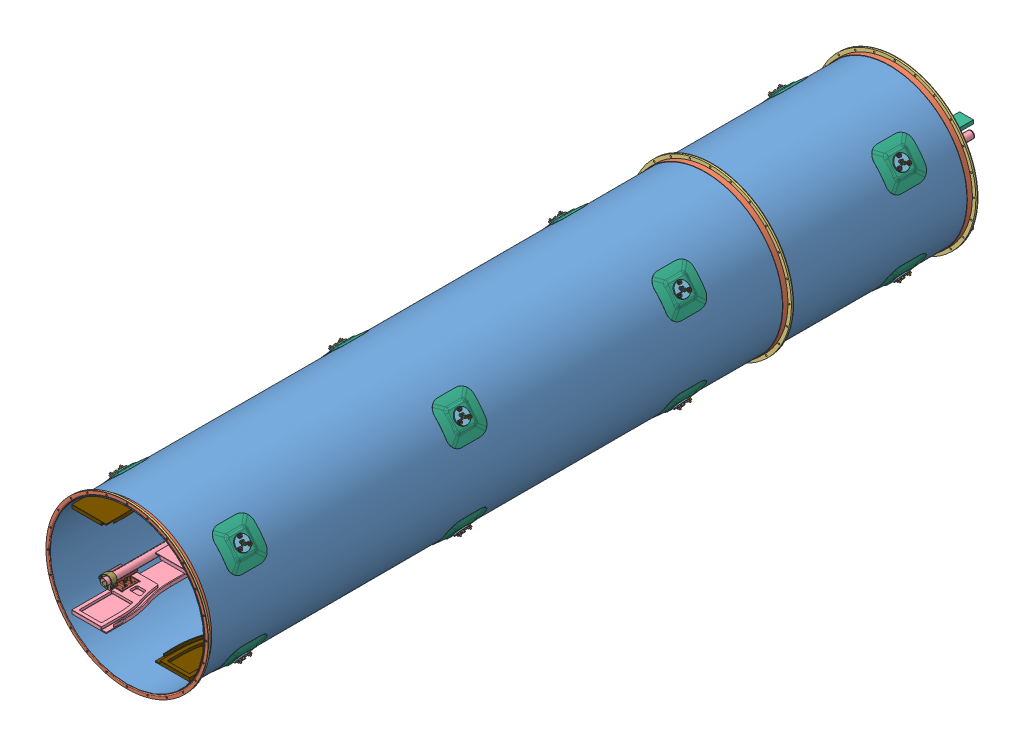
SolidWorks assembly Pixel_Insertion_Tube_asm_no_fix, configuration Default. Lengths in mm.
Overall size (454.65 454.65 2208.1).
343 component instances, 26 part files, 15 mates.
Components (placement in the parent):
- Pixel_Insertion_Tube-1: Pixel_Insertion_Tube [Default] at (0 0 -5) size (432 432 2158)
- IDS Small Flange Assy-1: IDS Small Flange Assy [Default] at (0 0 -567) x (-1 0 0) z (0 0 -1) size (454.65 454.65 20)
  - IDS Small Flange Shell-1: IDS Small Flange Shell [Default] at origin size (454.65 454.65 20)
  - IDS Small Ring-1: IDS Small Ring [Thinner] at (0 0 -6) size (454.65 454.65 4.7)
- IDS Small Flange Assy-2: IDS Small Flange Assy [Default] at (0 0 1074) x (-1 0 0) z (0 0 1) size (454.65 454.65 20)
  - IDS Small Flange Shell-1: IDS Small Flange Shell [Default] at origin size (454.65 454.65 20)
  - IDS Small Ring-1: IDS Small Ring [Thinner] at (0 0 -6) size (454.65 454.65 4.7)
- IDS Small Flange Assy-3: IDS Small Flange Assy [Default] at (0 0 -1084) x (-1 0 0) z (0 0 -1) size (454.65 454.65 20)
  - IDS Small Flange Shell-1: IDS Small Flange Shell [Default] at origin size (454.65 454.65 20)
  - IDS Small Ring-1: IDS Small Ring [Thinner] at (0 0 -6) size (454.65 454.65 4.7)
- PIT_rail_20mm_assembly_no_fix-1: PIT_rail_20mm_assembly_no_fix [on pit] at (0 0 -1134.1) size (415.12 363.39 2198)
  - PIT_rail_rc-1: PIT_rail_rc [TN] at (-158 94 2) size (138.56 101.58 2198)
    - rc-1: rc [Default] at origin size (20 20 2114)
    - rc_mount-1: rc_mount [PIT] at (0 0 208.1) size (80.85 96.81 113.59)
      - PIT_rail_foot_v2-1: PIT_rail_foot_v2 [PIT] at (-6.1826 36.9354 0) x (0.623502 0.781822 0) z (0 0 1) size (113.62 41.63 113.59)
        - PIT_rail_arm_achor_post_v2-1: PIT_rail_arm_achor_post_v2 [Default] at origin size (40 13.24 40)
        - PIT_foot_composit_v6-1: PIT_foot_composit_v6 [Default] at (0 3.7433 0) x (0 -1 0) z (0 0 1) size (12.8 113.62 113.59)
        - PIT_rail_hanger_ext_v3-1: PIT_rail_hanger_ext_v3 [Default] at (0 5.7433 -28.8) x (0 -1 0) z (0 0 1) (suppressed, hidden)
        - HX-SHCS 0.164-32x1x1-N-1: HX-SHCS 0.164-32x1x1-N [HX-SHCS 0.164-32x1x1-N] at (-3.5355 17.4089 3.5355) x (0 -1 0) z (0.991685 0 -0.128686) size (29.57 6.86 6.86)
        - HX-SHCS 0.164-32x1x1-N-2: HX-SHCS 0.164-32x1x1-N [HX-SHCS 0.164-32x1x1-N] at (3.5355 17.4089 -3.5355) x (0 -1 0) z (0 0 1) size (29.57 6.86 6.86)
        - HI-TIGUE-HLT452-5-3-1: HI-TIGUE-HLT452-5-3 [Default] at (15.5 6.9433 0) x (-0.837169 0 -0.546944) z (-0.546944 0 0.837169) size (7.98 14.34 7.98)
        - HI-TIGUE-HLT452-5-3-2: HI-TIGUE-HLT452-5-3 [Default] at (-7.75 6.9433 13.4234) x (-0.837169 0 -0.546944) z (-0.546944 0 0.837169) size (7.98 14.34 7.98)
        - HI-TIGUE-HLT452-5-3-3: HI-TIGUE-HLT452-5-3 [Default] at (-7.75 6.9433 -13.4234) x (-0.837169 0 -0.546944) z (-0.546944 0 0.837169) size (7.98 14.34 7.98)
        - MSHXNUT 0.190-32-S-N-1: MSHXNUT 0.190-32-S-N [MSHXNUT 0.190-32-S-N] at (-7.75 16.5453 -13.4234) x (1 0 0) z (0 1 0) size (9.53 11 3.3)
        - MSHXNUT 0.190-32-S-N-2: MSHXNUT 0.190-32-S-N [MSHXNUT 0.190-32-S-N] at (15.5 16.5453 0) x (1 0 0) z (0 1 0) size (9.53 11 3.3)
        - MSHXNUT 0.190-32-S-N-3: MSHXNUT 0.190-32-S-N [MSHXNUT 0.190-32-S-N] at (-7.75 16.5453 13.4234) x (0.673341 0 -0.739332) z (0 1 0) size (9.53 11 3.3)
        - PIT_rail_hanger_ext_mirror_v3-1: PIT_rail_hanger_ext_mirror_v3 [Default] at (0 5.7433 28.8) x (0 -1 0) z (0 0 1) (suppressed, hidden)
        - rail_mount_dowel_pin-1: rail_mount_dowel_pin [long] at (-3.5355 -6 -3.5355) size (3.18 32 3.18)
      - PIT_rail_arm_20mm_v2-1: PIT_rail_arm_20mm_v2 [Default] at origin size (30.35 35.91 64.06)
    - rc_mount-2: rc_mount [PIT] at (0 0 824.1) size (80.85 96.81 113.59)
      - PIT_rail_foot_v2-1: PIT_rail_foot_v2 [PIT] at (-6.1826 36.9354 0) x (0.623502 0.781822 0) z (0 0 1) size (113.62 41.63 113.59)
        - PIT_rail_arm_achor_post_v2-1: PIT_rail_arm_achor_post_v2 [Default] at origin size (40 13.24 40)
        - PIT_foot_composit_v6-1: PIT_foot_composit_v6 [Default] at (0 3.7433 0) x (0 -1 0) z (0 0 1) size (12.8 113.62 113.59)
        - PIT_rail_hanger_ext_v3-1: PIT_rail_hanger_ext_v3 [Default] at (0 5.7433 -28.8) x (0 -1 0) z (0 0 1) (suppressed, hidden)
        - HX-SHCS 0.164-32x1x1-N-1: HX-SHCS 0.164-32x1x1-N [HX-SHCS 0.164-32x1x1-N] at (-3.5355 17.4089 3.5355) x (0 -1 0) z (0.991685 0 -0.128686) size (29.57 6.86 6.86)
        - HX-SHCS 0.164-32x1x1-N-2: HX-SHCS 0.164-32x1x1-N [HX-SHCS 0.164-32x1x1-N] at (3.5355 17.4089 -3.5355) x (0 -1 0) z (0 0 1) size (29.57 6.86 6.86)
        - HI-TIGUE-HLT452-5-3-1: HI-TIGUE-HLT452-5-3 [Default] at (15.5 6.9433 0) x (-0.837169 0 -0.546944) z (-0.546944 0 0.837169) size (7.98 14.34 7.98)
        - HI-TIGUE-HLT452-5-3-2: HI-TIGUE-HLT452-5-3 [Default] at (-7.75 6.9433 13.4234) x (-0.837169 0 -0.546944) z (-0.546944 0 0.837169) size (7.98 14.34 7.98)
        - HI-TIGUE-HLT452-5-3-3: HI-TIGUE-HLT452-5-3 [Default] at (-7.75 6.9433 -13.4234) x (-0.837169 0 -0.546944) z (-0.546944 0 0.837169) size (7.98 14.34 7.98)
        - MSHXNUT 0.190-32-S-N-1: MSHXNUT 0.190-32-S-N [MSHXNUT 0.190-32-S-N] at (-7.75 16.5453 -13.4234) x (1 0 0) z (0 1 0) size (9.53 11 3.3)
        - MSHXNUT 0.190-32-S-N-2: MSHXNUT 0.190-32-S-N [MSHXNUT 0.190-32-S-N] at (15.5 16.5453 0) x (1 0 0) z (0 1 0) size (9.53 11 3.3)
        - MSHXNUT 0.190-32-S-N-3: MSHXNUT 0.190-32-S-N [MSHXNUT 0.190-32-S-N] at (-7.75 16.5453 13.4234) x (0.673341 0 -0.739332) z (0 1 0) size (9.53 11 3.3)
        - PIT_rail_hanger_ext_mirror_v3-1: PIT_rail_hanger_ext_mirror_v3 [Default] at (0 5.7433 28.8) x (0 -1 0) z (0 0 1) (suppressed, hidden)
        - rail_mount_dowel_pin-1: rail_mount_dowel_pin [long] at (-3.5355 -6 -3.5355) size (3.18 32 3.18)
      - PIT_rail_arm_20mm_v2-1: PIT_rail_arm_20mm_v2 [Default] at origin size (30.35 35.91 64.06)
    - rc_mount-3: rc_mount [PIT] at (0 0 1440.1) size (80.85 96.81 113.59)
      - PIT_rail_foot_v2-1: PIT_rail_foot_v2 [PIT] at (-6.1826 36.9354 0) x (0.623502 0.781822 0) z (0 0 1) size (113.62 41.63 113.59)
        - PIT_rail_arm_achor_post_v2-1: PIT_rail_arm_achor_post_v2 [Default] at origin size (40 13.24 40)
        - PIT_foot_composit_v6-1: PIT_foot_composit_v6 [Default] at (0 3.7433 0) x (0 -1 0) z (0 0 1) size (12.8 113.62 113.59)
        - PIT_rail_hanger_ext_v3-1: PIT_rail_hanger_ext_v3 [Default] at (0 5.7433 -28.8) x (0 -1 0) z (0 0 1) (suppressed, hidden)
        - HX-SHCS 0.164-32x1x1-N-1: HX-SHCS 0.164-32x1x1-N [HX-SHCS 0.164-32x1x1-N] at (-3.5355 17.4089 3.5355) x (0 -1 0) z (0.991685 0 -0.128686) size (29.57 6.86 6.86)
        - HX-SHCS 0.164-32x1x1-N-2: HX-SHCS 0.164-32x1x1-N [HX-SHCS 0.164-32x1x1-N] at (3.5355 17.4089 -3.5355) x (0 -1 0) z (0 0 1) size (29.57 6.86 6.86)
        - HI-TIGUE-HLT452-5-3-1: HI-TIGUE-HLT452-5-3 [Default] at (15.5 6.9433 0) x (-0.837169 0 -0.546944) z (-0.546944 0 0.837169) size (7.98 14.34 7.98)
        - HI-TIGUE-HLT452-5-3-2: HI-TIGUE-HLT452-5-3 [Default] at (-7.75 6.9433 13.4234) x (-0.837169 0 -0.546944) z (-0.546944 0 0.837169) size (7.98 14.34 7.98)
        - HI-TIGUE-HLT452-5-3-3: HI-TIGUE-HLT452-5-3 [Default] at (-7.75 6.9433 -13.4234) x (-0.837169 0 -0.546944) z (-0.546944 0 0.837169) size (7.98 14.34 7.98)
        - MSHXNUT 0.190-32-S-N-1: MSHXNUT 0.190-32-S-N [MSHXNUT 0.190-32-S-N] at (-7.75 16.5453 -13.4234) x (1 0 0) z (0 1 0) size (9.53 11 3.3)
        - MSHXNUT 0.190-32-S-N-2: MSHXNUT 0.190-32-S-N [MSHXNUT 0.190-32-S-N] at (15.5 16.5453 0) x (1 0 0) z (0 1 0) size (9.53 11 3.3)
        - MSHXNUT 0.190-32-S-N-3: MSHXNUT 0.190-32-S-N [MSHXNUT 0.190-32-S-N] at (-7.75 16.5453 13.4234) x (0.673341 0 -0.739332) z (0 1 0) size (9.53 11 3.3)
        - PIT_rail_hanger_ext_mirror_v3-1: PIT_rail_hanger_ext_mirror_v3 [Default] at (0 5.7433 28.8) x (0 -1 0) z (0 0 1) (suppressed, hidden)
        - rail_mount_dowel_pin-1: rail_mount_dowel_pin [long] at (-3.5355 -6 -3.5355) size (3.18 32 3.18)
      - PIT_rail_arm_20mm_v2-1: PIT_rail_arm_20mm_v2 [Default] at origin size (30.35 35.91 64.06)
    - rc_mount-4: rc_mount [PIT] at (0 0 2056.1) size (80.85 96.81 113.59)
      - PIT_rail_foot_v2-1: PIT_rail_foot_v2 [PIT] at (-6.1826 36.9354 0) x (0.623502 0.781822 0) z (0 0 1) size (113.62 41.63 113.59)
        - PIT_rail_arm_achor_post_v2-1: PIT_rail_arm_achor_post_v2 [Default] at origin size (40 13.24 40)
        - PIT_foot_composit_v6-1: PIT_foot_composit_v6 [Default] at (0 3.7433 0) x (0 -1 0) z (0 0 1) size (12.8 113.62 113.59)
        - PIT_rail_hanger_ext_v3-1: PIT_rail_hanger_ext_v3 [Default] at (0 5.7433 -28.8) x (0 -1 0) z (0 0 1) (suppressed, hidden)
        - HX-SHCS 0.164-32x1x1-N-1: HX-SHCS 0.164-32x1x1-N [HX-SHCS 0.164-32x1x1-N] at (-3.5355 17.4089 3.5355) x (0 -1 0) z (0.991685 0 -0.128686) size (29.57 6.86 6.86)
        - HX-SHCS 0.164-32x1x1-N-2: HX-SHCS 0.164-32x1x1-N [HX-SHCS 0.164-32x1x1-N] at (3.5355 17.4089 -3.5355) x (0 -1 0) z (0 0 1) size (29.57 6.86 6.86)
        - HI-TIGUE-HLT452-5-3-1: HI-TIGUE-HLT452-5-3 [Default] at (15.5 6.9433 0) x (-0.837169 0 -0.546944) z (-0.546944 0 0.837169) size (7.98 14.34 7.98)
        - HI-TIGUE-HLT452-5-3-2: HI-TIGUE-HLT452-5-3 [Default] at (-7.75 6.9433 13.4234) x (-0.837169 0 -0.546944) z (-0.546944 0 0.837169) size (7.98 14.34 7.98)
        - HI-TIGUE-HLT452-5-3-3: HI-TIGUE-HLT452-5-3 [Default] at (-7.75 6.9433 -13.4234) x (-0.837169 0 -0.546944) z (-0.546944 0 0.837169) size (7.98 14.34 7.98)
        - MSHXNUT 0.190-32-S-N-1: MSHXNUT 0.190-32-S-N [MSHXNUT 0.190-32-S-N] at (-7.75 16.5453 -13.4234) x (1 0 0) z (0 1 0) size (9.53 11 3.3)
        - MSHXNUT 0.190-32-S-N-2: MSHXNUT 0.190-32-S-N [MSHXNUT 0.190-32-S-N] at (15.5 16.5453 0) x (1 0 0) z (0 1 0) size (9.53 11 3.3)
        - MSHXNUT 0.190-32-S-N-3: MSHXNUT 0.190-32-S-N [MSHXNUT 0.190-32-S-N] at (-7.75 16.5453 13.4234) x (0.673341 0 -0.739332) z (0 1 0) size (9.53 11 3.3)
        - PIT_rail_hanger_ext_mirror_v3-1: PIT_rail_hanger_ext_mirror_v3 [Default] at (0 5.7433 28.8) x (0 -1 0) z (0 0 1) (suppressed, hidden)
        - rail_mount_dowel_pin-1: rail_mount_dowel_pin [long] at (-3.5355 -6 -3.5355) size (3.18 32 3.18)
      - PIT_rail_arm_20mm_v2-1: PIT_rail_arm_20mm_v2 [Default] at origin size (30.35 35.91 64.06)
    - rc_carriage_stop-1: rc_carriage_stop [Default] at (0 0 2095.6) size (34.67 34.78 62.88)
      - stop_clamp-1: stop_clamp [rc] at origin size (33.3 34.78 15)
      - stop_post-1: stop_post [rc] at (-16.5 0 -7.5) x (-0.987548 -0.157317 0) z (0 0 -1) size (7 7 62.88)
      - socket head cap screw_ai-1: socket head cap screw_ai [HX-SHCS 0.164-32x0.5x0.5-N] at (8.1656 16.2138 0) x (-1 0 0) z (0 -0.924225 -0.381849) size (16.87 6.86 6.86)
      - machine screw nut hex_ai-1: machine screw nut hex_ai [MSHXNUT 0.125-40-S-N] at (-16.5 0 10.3956) x (-0.451241 0.892402 0) z (0 0 1) size (7.92 9.15 2.9)
    - rc_nut_full-1: rc_nut_full [Default] at (0 0 2056.1) size (15.76 6.44 110)
    - rc_nut_full-2: rc_nut_full [Default] at (0 0 1440.1) size (15.76 6.44 110)
    - rc_nut_full-3: rc_nut_full [Default] at (0 0 208.1) size (15.76 6.44 110)
    - rc_nut_full-4: rc_nut_full [Default] at (0 0 824.1) size (15.76 6.44 110)
    - taper_pin_female_20mm-1: taper_pin_female_20mm [Default] at (0 0 -2) x (-0.558756 0.829332 0) z (0 0 1) size (20 20 23.1)
    - cam_rail_TR_1-1: cam_rail_TR_1 [v2] at (158.1 39 2196) size (96 10 755.6)
    - cam_rail_TR_2-1: cam_rail_TR_2 [v2] at (158.1 39 2196) size (72 10 615.4)
    - cam_rail_TR_3-1: cam_rail_TR_3 [v2] at (158.1 39 2196) size (39 10 825.8)
    - cam_rail_TL_1_v2-1: cam_rail_TL_1_v2 [v2] at (172.1 39 2196) (suppressed, hidden)
    - cam_rail_TL_2_v2-1: cam_rail_TL_2_v2 [v2] at (172.1 39 2196) (suppressed, hidden)
    - cam_rail_TL_3_v2-1: cam_rail_TL_3_v2 [v2] at (172.1 39 2196) (suppressed, hidden)
    - shoulder_screw_8-32_MC_95446A220-1: shoulder_screw_8-32_MC_95446A220 [95446A220] at (-2 39.175 841.1) x (0.999652 0 -0.026389) z (0.026389 0 0.999652) size (7.94 12.24 7.94)
  - PIT_rail_rc-2: PIT_rail_rc [TS] at (158 94 2) size (138.56 101.58 2198)
    - rc-1: rc [Default] at origin size (20 20 2114)
    - rc_mount-1: rc_mount [PIT] at (0 0 208.1) x (-1 0 0) z (0 0 -1) size (80.85 96.81 113.59)
      - PIT_rail_foot_v2-1: PIT_rail_foot_v2 [PIT] at (-6.1826 36.9354 0) x (0.623502 0.781822 0) z (0 0 1) size (113.62 41.63 113.59)
        - PIT_rail_arm_achor_post_v2-1: PIT_rail_arm_achor_post_v2 [Default] at origin size (40 13.24 40)
        - PIT_foot_composit_v6-1: PIT_foot_composit_v6 [Default] at (0 3.7433 0) x (0 -1 0) z (0 0 1) size (12.8 113.62 113.59)
        - PIT_rail_hanger_ext_v3-1: PIT_rail_hanger_ext_v3 [Default] at (0 5.7433 -28.8) x (0 -1 0) z (0 0 1) (suppressed, hidden)
        - HX-SHCS 0.164-32x1x1-N-1: HX-SHCS 0.164-32x1x1-N [HX-SHCS 0.164-32x1x1-N] at (-3.5355 17.4089 3.5355) x (0 -1 0) z (0.991685 0 -0.128686) size (29.57 6.86 6.86)
        - HX-SHCS 0.164-32x1x1-N-2: HX-SHCS 0.164-32x1x1-N [HX-SHCS 0.164-32x1x1-N] at (3.5355 17.4089 -3.5355) x (0 -1 0) z (0 0 1) size (29.57 6.86 6.86)
        - HI-TIGUE-HLT452-5-3-1: HI-TIGUE-HLT452-5-3 [Default] at (15.5 6.9433 0) x (-0.837169 0 -0.546944) z (-0.546944 0 0.837169) size (7.98 14.34 7.98)
        - HI-TIGUE-HLT452-5-3-2: HI-TIGUE-HLT452-5-3 [Default] at (-7.75 6.9433 13.4234) x (-0.837169 0 -0.546944) z (-0.546944 0 0.837169) size (7.98 14.34 7.98)
        - HI-TIGUE-HLT452-5-3-3: HI-TIGUE-HLT452-5-3 [Default] at (-7.75 6.9433 -13.4234) x (-0.837169 0 -0.546944) z (-0.546944 0 0.837169) size (7.98 14.34 7.98)
        - MSHXNUT 0.190-32-S-N-1: MSHXNUT 0.190-32-S-N [MSHXNUT 0.190-32-S-N] at (-7.75 16.5453 -13.4234) x (1 0 0) z (0 1 0) size (9.53 11 3.3)
        - MSHXNUT 0.190-32-S-N-2: MSHXNUT 0.190-32-S-N [MSHXNUT 0.190-32-S-N] at (15.5 16.5453 0) x (1 0 0) z (0 1 0) size (9.53 11 3.3)
        - MSHXNUT 0.190-32-S-N-3: MSHXNUT 0.190-32-S-N [MSHXNUT 0.190-32-S-N] at (-7.75 16.5453 13.4234) x (0.673341 0 -0.739332) z (0 1 0) size (9.53 11 3.3)
        - PIT_rail_hanger_ext_mirror_v3-1: PIT_rail_hanger_ext_mirror_v3 [Default] at (0 5.7433 28.8) x (0 -1 0) z (0 0 1) (suppressed, hidden)
        - rail_mount_dowel_pin-1: rail_mount_dowel_pin [long] at (-3.5355 -6 -3.5355) size (3.18 32 3.18)
      - PIT_rail_arm_20mm_v2-1: PIT_rail_arm_20mm_v2 [Default] at origin size (30.35 35.91 64.06)
    - rc_mount-2: rc_mount [PIT] at (0 0 824.1) x (-1 0 0) z (0 0 -1) size (80.85 96.81 113.59)
      - PIT_rail_foot_v2-1: PIT_rail_foot_v2 [PIT] at (-6.1826 36.9354 0) x (0.623502 0.781822 0) z (0 0 1) size (113.62 41.63 113.59)
        - PIT_rail_arm_achor_post_v2-1: PIT_rail_arm_achor_post_v2 [Default] at origin size (40 13.24 40)
        - PIT_foot_composit_v6-1: PIT_foot_composit_v6 [Default] at (0 3.7433 0) x (0 -1 0) z (0 0 1) size (12.8 113.62 113.59)
        - PIT_rail_hanger_ext_v3-1: PIT_rail_hanger_ext_v3 [Default] at (0 5.7433 -28.8) x (0 -1 0) z (0 0 1) (suppressed, hidden)
        - HX-SHCS 0.164-32x1x1-N-1: HX-SHCS 0.164-32x1x1-N [HX-SHCS 0.164-32x1x1-N] at (-3.5355 17.4089 3.5355) x (0 -1 0) z (0.991685 0 -0.128686) size (29.57 6.86 6.86)
        - HX-SHCS 0.164-32x1x1-N-2: HX-SHCS 0.164-32x1x1-N [HX-SHCS 0.164-32x1x1-N] at (3.5355 17.4089 -3.5355) x (0 -1 0) z (0 0 1) size (29.57 6.86 6.86)
        - HI-TIGUE-HLT452-5-3-1: HI-TIGUE-HLT452-5-3 [Default] at (15.5 6.9433 0) x (-0.837169 0 -0.546944) z (-0.546944 0 0.837169) size (7.98 14.34 7.98)
        - HI-TIGUE-HLT452-5-3-2: HI-TIGUE-HLT452-5-3 [Default] at (-7.75 6.9433 13.4234) x (-0.837169 0 -0.546944) z (-0.546944 0 0.837169) size (7.98 14.34 7.98)
        - HI-TIGUE-HLT452-5-3-3: HI-TIGUE-HLT452-5-3 [Default] at (-7.75 6.9433 -13.4234) x (-0.837169 0 -0.546944) z (-0.546944 0 0.837169) size (7.98 14.34 7.98)
        - MSHXNUT 0.190-32-S-N-1: MSHXNUT 0.190-32-S-N [MSHXNUT 0.190-32-S-N] at (-7.75 16.5453 -13.4234) x (1 0 0) z (0 1 0) size (9.53 11 3.3)
        - MSHXNUT 0.190-32-S-N-2: MSHXNUT 0.190-32-S-N [MSHXNUT 0.190-32-S-N] at (15.5 16.5453 0) x (1 0 0) z (0 1 0) size (9.53 11 3.3)
        - MSHXNUT 0.190-32-S-N-3: MSHXNUT 0.190-32-S-N [MSHXNUT 0.190-32-S-N] at (-7.75 16.5453 13.4234) x (0.673341 0 -0.739332) z (0 1 0) size (9.53 11 3.3)
        - PIT_rail_hanger_ext_mirror_v3-1: PIT_rail_hanger_ext_mirror_v3 [Default] at (0 5.7433 28.8) x (0 -1 0) z (0 0 1) (suppressed, hidden)
        - rail_mount_dowel_pin-1: rail_mount_dowel_pin [long] at (-3.5355 -6 -3.5355) size (3.18 32 3.18)
      - PIT_rail_arm_20mm_v2-1: PIT_rail_arm_20mm_v2 [Default] at origin size (30.35 35.91 64.06)
    - rc_mount-3: rc_mount [PIT] at (0 0 1440.1) x (-1 0 0) z (0 0 -1) size (80.85 96.81 113.59)
      - PIT_rail_foot_v2-1: PIT_rail_foot_v2 [PIT] at (-6.1826 36.9354 0) x (0.623502 0.781822 0) z (0 0 1) size (113.62 41.63 113.59)
        - PIT_rail_arm_achor_post_v2-1: PIT_rail_arm_achor_post_v2 [Default] at origin size (40 13.24 40)
        - PIT_foot_composit_v6-1: PIT_foot_composit_v6 [Default] at (0 3.7433 0) x (0 -1 0) z (0 0 1) size (12.8 113.62 113.59)
        - PIT_rail_hanger_ext_v3-1: PIT_rail_hanger_ext_v3 [Default] at (0 5.7433 -28.8) x (0 -1 0) z (0 0 1) (suppressed, hidden)
        - HX-SHCS 0.164-32x1x1-N-1: HX-SHCS 0.164-32x1x1-N [HX-SHCS 0.164-32x1x1-N] at (-3.5355 17.4089 3.5355) x (0 -1 0) z (0.991685 0 -0.128686) size (29.57 6.86 6.86)
        - HX-SHCS 0.164-32x1x1-N-2: HX-SHCS 0.164-32x1x1-N [HX-SHCS 0.164-32x1x1-N] at (3.5355 17.4089 -3.5355) x (0 -1 0) z (0 0 1) size (29.57 6.86 6.86)
        - HI-TIGUE-HLT452-5-3-1: HI-TIGUE-HLT452-5-3 [Default] at (15.5 6.9433 0) x (-0.837169 0 -0.546944) z (-0.546944 0 0.837169) size (7.98 14.34 7.98)
        - HI-TIGUE-HLT452-5-3-2: HI-TIGUE-HLT452-5-3 [Default] at (-7.75 6.9433 13.4234) x (-0.837169 0 -0.546944) z (-0.546944 0 0.837169) size (7.98 14.34 7.98)
        - HI-TIGUE-HLT452-5-3-3: HI-TIGUE-HLT452-5-3 [Default] at (-7.75 6.9433 -13.4234) x (-0.837169 0 -0.546944) z (-0.546944 0 0.837169) size (7.98 14.34 7.98)
        - MSHXNUT 0.190-32-S-N-1: MSHXNUT 0.190-32-S-N [MSHXNUT 0.190-32-S-N] at (-7.75 16.5453 -13.4234) x (1 0 0) z (0 1 0) size (9.53 11 3.3)
        - MSHXNUT 0.190-32-S-N-2: MSHXNUT 0.190-32-S-N [MSHXNUT 0.190-32-S-N] at (15.5 16.5453 0) x (1 0 0) z (0 1 0) size (9.53 11 3.3)
        - MSHXNUT 0.190-32-S-N-3: MSHXNUT 0.190-32-S-N [MSHXNUT 0.190-32-S-N] at (-7.75 16.5453 13.4234) x (0.673341 0 -0.739332) z (0 1 0) size (9.53 11 3.3)
        - PIT_rail_hanger_ext_mirror_v3-1: PIT_rail_hanger_ext_mirror_v3 [Default] at (0 5.7433 28.8) x (0 -1 0) z (0 0 1) (suppressed, hidden)
        - rail_mount_dowel_pin-1: rail_mount_dowel_pin [long] at (-3.5355 -6 -3.5355) size (3.18 32 3.18)
      - PIT_rail_arm_20mm_v2-1: PIT_rail_arm_20mm_v2 [Default] at origin size (30.35 35.91 64.06)
    - rc_mount-4: rc_mount [PIT] at (0 0 2056.1) x (-1 0 0) z (0 0 -1) size (80.85 96.81 113.59)
      - PIT_rail_foot_v2-1: PIT_rail_foot_v2 [PIT] at (-6.1826 36.9354 0) x (0.623502 0.781822 0) z (0 0 1) size (113.62 41.63 113.59)
        - PIT_rail_arm_achor_post_v2-1: PIT_rail_arm_achor_post_v2 [Default] at origin size (40 13.24 40)
        - PIT_foot_composit_v6-1: PIT_foot_composit_v6 [Default] at (0 3.7433 0) x (0 -1 0) z (0 0 1) size (12.8 113.62 113.59)
        - PIT_rail_hanger_ext_v3-1: PIT_rail_hanger_ext_v3 [Default] at (0 5.7433 -28.8) x (0 -1 0) z (0 0 1) (suppressed, hidden)
        - HX-SHCS 0.164-32x1x1-N-1: HX-SHCS 0.164-32x1x1-N [HX-SHCS 0.164-32x1x1-N] at (-3.5355 17.4089 3.5355) x (0 -1 0) z (0.991685 0 -0.128686) size (29.57 6.86 6.86)
        - HX-SHCS 0.164-32x1x1-N-2: HX-SHCS 0.164-32x1x1-N [HX-SHCS 0.164-32x1x1-N] at (3.5355 17.4089 -3.5355) x (0 -1 0) z (0 0 1) size (29.57 6.86 6.86)
        - HI-TIGUE-HLT452-5-3-1: HI-TIGUE-HLT452-5-3 [Default] at (15.5 6.9433 0) x (-0.837169 0 -0.546944) z (-0.546944 0 0.837169) size (7.98 14.34 7.98)
        - HI-TIGUE-HLT452-5-3-2: HI-TIGUE-HLT452-5-3 [Default] at (-7.75 6.9433 13.4234) x (-0.837169 0 -0.546944) z (-0.546944 0 0.837169) size (7.98 14.34 7.98)
        - HI-TIGUE-HLT452-5-3-3: HI-TIGUE-HLT452-5-3 [Default] at (-7.75 6.9433 -13.4234) x (-0.837169 0 -0.546944) z (-0.546944 0 0.837169) size (7.98 14.34 7.98)
        - MSHXNUT 0.190-32-S-N-1: MSHXNUT 0.190-32-S-N [MSHXNUT 0.190-32-S-N] at (-7.75 16.5453 -13.4234) x (1 0 0) z (0 1 0) size (9.53 11 3.3)
        - MSHXNUT 0.190-32-S-N-2: MSHXNUT 0.190-32-S-N [MSHXNUT 0.190-32-S-N] at (15.5 16.5453 0) x (1 0 0) z (0 1 0) size (9.53 11 3.3)
        - MSHXNUT 0.190-32-S-N-3: MSHXNUT 0.190-32-S-N [MSHXNUT 0.190-32-S-N] at (-7.75 16.5453 13.4234) x (0.673341 0 -0.739332) z (0 1 0) size (9.53 11 3.3)
        - PIT_rail_hanger_ext_mirror_v3-1: PIT_rail_hanger_ext_mirror_v3 [Default] at (0 5.7433 28.8) x (0 -1 0) z (0 0 1) (suppressed, hidden)
        - rail_mount_dowel_pin-1: rail_mount_dowel_pin [long] at (-3.5355 -6 -3.5355) size (3.18 32 3.18)
      - PIT_rail_arm_20mm_v2-1: PIT_rail_arm_20mm_v2 [Default] at origin size (30.35 35.91 64.06)
    - rc_carriage_stop-1: rc_carriage_stop [flip] at (0 0 2095.6) x (-1 0 0) z (0 0 -1) size (33.66 34.78 62.88)
      - stop_clamp-1: stop_clamp [rc] at origin size (33.3 34.78 15)
      - stop_post-1: stop_post [rc] at (-16.5 0 7.5) x (-0.972486 -0.232961 0) z (0 0 1) size (7 7 62.88)
      - socket head cap screw_ai-1: socket head cap screw_ai [HX-SHCS 0.164-32x0.5x0.5-N] at (8.1656 16.2138 0) x (-1 0 0) z (0 -0.924225 -0.381849) size (16.87 6.86 6.86)
      - machine screw nut hex_ai-1: machine screw nut hex_ai [MSHXNUT 0.125-40-S-N] at (-16.5 0 -10.3956) x (-0.074991 -0.997184 0) z (0 0 -1) size (7.92 9.15 2.9)
    - rc_nut_full-1: rc_nut_full [Default] at (0 0 2056.1) size (15.76 6.44 110)
    - rc_nut_full-2: rc_nut_full [Default] at (0 0 1440.1) size (15.76 6.44 110)
    - rc_nut_full-3: rc_nut_full [Default] at (0 0 208.1) size (15.76 6.44 110)
    - rc_nut_full-4: rc_nut_full [Default] at (0 0 824.1) size (15.76 6.44 110)
    - taper_pin_female_20mm-1: taper_pin_female_20mm [Default] at (0 0 -2) x (-0.558756 0.829332 0) z (0 0 1) size (20 20 23.1)
    - cam_rail_TR_1-1: cam_rail_TR_1 [v2] at (158.1 39 2196) size (96 10 755.6) (suppressed, hidden)
    - cam_rail_TR_2-1: cam_rail_TR_2 [v2] at (158.1 39 2196) size (72 10 615.4) (suppressed, hidden)
    - cam_rail_TR_3-1: cam_rail_TR_3 [v2] at (158.1 39 2196) size (39 10 825.8) (suppressed, hidden)
    - cam_rail_TL_1_v2-1: cam_rail_TL_1_v2 [v2] at (172.1 39 2196)
    - cam_rail_TL_2_v2-1: cam_rail_TL_2_v2 [v2] at (172.1 39 2196)
    - cam_rail_TL_3_v2-1: cam_rail_TL_3_v2 [v2] at (172.1 39 2196)
    - shoulder_screw_8-32_MC_95446A220-1: shoulder_screw_8-32_MC_95446A220 [95446A220] at (2 39.175 807.1) x (0.999652 0 -0.026389) z (0.026389 0 0.999652) size (7.94 12.24 7.94)
  - PIT_rail_rc-4: PIT_rail_rc [TS] at (-158 -94 2) x (-1 0 0) z (0 0 1) size (138.56 101.58 2198)
    - rc-1: rc [Default] at origin size (20 20 2114)
    - rc_mount-1: rc_mount [PIT] at (0 0 208.1) x (-1 0 0) z (0 0 -1) size (80.85 96.81 113.59)
      - PIT_rail_foot_v2-1: PIT_rail_foot_v2 [PIT] at (-6.1826 36.9354 0) x (0.623502 0.781822 0) z (0 0 1) size (113.62 41.63 113.59)
        - PIT_rail_arm_achor_post_v2-1: PIT_rail_arm_achor_post_v2 [Default] at origin size (40 13.24 40)
        - PIT_foot_composit_v6-1: PIT_foot_composit_v6 [Default] at (0 3.7433 0) x (0 -1 0) z (0 0 1) size (12.8 113.62 113.59)
        - PIT_rail_hanger_ext_v3-1: PIT_rail_hanger_ext_v3 [Default] at (0 5.7433 -28.8) x (0 -1 0) z (0 0 1) (suppressed, hidden)
        - HX-SHCS 0.164-32x1x1-N-1: HX-SHCS 0.164-32x1x1-N [HX-SHCS 0.164-32x1x1-N] at (-3.5355 17.4089 3.5355) x (0 -1 0) z (0.991685 0 -0.128686) size (29.57 6.86 6.86)
        - HX-SHCS 0.164-32x1x1-N-2: HX-SHCS 0.164-32x1x1-N [HX-SHCS 0.164-32x1x1-N] at (3.5355 17.4089 -3.5355) x (0 -1 0) z (0 0 1) size (29.57 6.86 6.86)
        - HI-TIGUE-HLT452-5-3-1: HI-TIGUE-HLT452-5-3 [Default] at (15.5 6.9433 0) x (-0.837169 0 -0.546944) z (-0.546944 0 0.837169) size (7.98 14.34 7.98)
        - HI-TIGUE-HLT452-5-3-2: HI-TIGUE-HLT452-5-3 [Default] at (-7.75 6.9433 13.4234) x (-0.837169 0 -0.546944) z (-0.546944 0 0.837169) size (7.98 14.34 7.98)
        - HI-TIGUE-HLT452-5-3-3: HI-TIGUE-HLT452-5-3 [Default] at (-7.75 6.9433 -13.4234) x (-0.837169 0 -0.546944) z (-0.546944 0 0.837169) size (7.98 14.34 7.98)
        - MSHXNUT 0.190-32-S-N-1: MSHXNUT 0.190-32-S-N [MSHXNUT 0.190-32-S-N] at (-7.75 16.5453 -13.4234) x (1 0 0) z (0 1 0) size (9.53 11 3.3)
        - MSHXNUT 0.190-32-S-N-2: MSHXNUT 0.190-32-S-N [MSHXNUT 0.190-32-S-N] at (15.5 16.5453 0) x (1 0 0) z (0 1 0) size (9.53 11 3.3)
        - MSHXNUT 0.190-32-S-N-3: MSHXNUT 0.190-32-S-N [MSHXNUT 0.190-32-S-N] at (-7.75 16.5453 13.4234) x (0.673341 0 -0.739332) z (0 1 0) size (9.53 11 3.3)
        - PIT_rail_hanger_ext_mirror_v3-1: PIT_rail_hanger_ext_mirror_v3 [Default] at (0 5.7433 28.8) x (0 -1 0) z (0 0 1) (suppressed, hidden)
        - rail_mount_dowel_pin-1: rail_mount_dowel_pin [long] at (-3.5355 -6 -3.5355) size (3.18 32 3.18)
      - PIT_rail_arm_20mm_v2-1: PIT_rail_arm_20mm_v2 [Default] at origin size (30.35 35.91 64.06)
    - rc_mount-2: rc_mount [PIT] at (0 0 824.1) x (-1 0 0) z (0 0 -1) size (80.85 96.81 113.59)
      - PIT_rail_foot_v2-1: PIT_rail_foot_v2 [PIT] at (-6.1826 36.9354 0) x (0.623502 0.781822 0) z (0 0 1) size (113.62 41.63 113.59)
        - PIT_rail_arm_achor_post_v2-1: PIT_rail_arm_achor_post_v2 [Default] at origin size (40 13.24 40)
        - PIT_foot_composit_v6-1: PIT_foot_composit_v6 [Default] at (0 3.7433 0) x (0 -1 0) z (0 0 1) size (12.8 113.62 113.59)
        - PIT_rail_hanger_ext_v3-1: PIT_rail_hanger_ext_v3 [Default] at (0 5.7433 -28.8) x (0 -1 0) z (0 0 1) (suppressed, hidden)
        - HX-SHCS 0.164-32x1x1-N-1: HX-SHCS 0.164-32x1x1-N [HX-SHCS 0.164-32x1x1-N] at (-3.5355 17.4089 3.5355) x (0 -1 0) z (0.991685 0 -0.128686) size (29.57 6.86 6.86)
        - HX-SHCS 0.164-32x1x1-N-2: HX-SHCS 0.164-32x1x1-N [HX-SHCS 0.164-32x1x1-N] at (3.5355 17.4089 -3.5355) x (0 -1 0) z (0 0 1) size (29.57 6.86 6.86)
        - HI-TIGUE-HLT452-5-3-1: HI-TIGUE-HLT452-5-3 [Default] at (15.5 6.9433 0) x (-0.837169 0 -0.546944) z (-0.546944 0 0.837169) size (7.98 14.34 7.98)
        - HI-TIGUE-HLT452-5-3-2: HI-TIGUE-HLT452-5-3 [Default] at (-7.75 6.9433 13.4234) x (-0.837169 0 -0.546944) z (-0.546944 0 0.837169) size (7.98 14.34 7.98)
        - HI-TIGUE-HLT452-5-3-3: HI-TIGUE-HLT452-5-3 [Default] at (-7.75 6.9433 -13.4234) x (-0.837169 0 -0.546944) z (-0.546944 0 0.837169) size (7.98 14.34 7.98)
        - MSHXNUT 0.190-32-S-N-1: MSHXNUT 0.190-32-S-N [MSHXNUT 0.190-32-S-N] at (-7.75 16.5453 -13.4234) x (1 0 0) z (0 1 0) size (9.53 11 3.3)
        - MSHXNUT 0.190-32-S-N-2: MSHXNUT 0.190-32-S-N [MSHXNUT 0.190-32-S-N] at (15.5 16.5453 0) x (1 0 0) z (0 1 0) size (9.53 11 3.3)
        - MSHXNUT 0.190-32-S-N-3: MSHXNUT 0.190-32-S-N [MSHXNUT 0.190-32-S-N] at (-7.75 16.5453 13.4234) x (0.673341 0 -0.739332) z (0 1 0) size (9.53 11 3.3)
        - PIT_rail_hanger_ext_mirror_v3-1: PIT_rail_hanger_ext_mirror_v3 [Default] at (0 5.7433 28.8) x (0 -1 0) z (0 0 1) (suppressed, hidden)
        - rail_mount_dowel_pin-1: rail_mount_dowel_pin [long] at (-3.5355 -6 -3.5355) size (3.18 32 3.18)
      - PIT_rail_arm_20mm_v2-1: PIT_rail_arm_20mm_v2 [Default] at origin size (30.35 35.91 64.06)
    - rc_mount-3: rc_mount [PIT] at (0 0 1440.1) x (-1 0 0) z (0 0 -1) size (80.85 96.81 113.59)
      - PIT_rail_foot_v2-1: PIT_rail_foot_v2 [PIT] at (-6.1826 36.9354 0) x (0.623502 0.781822 0) z (0 0 1) size (113.62 41.63 113.59)
        - PIT_rail_arm_achor_post_v2-1: PIT_rail_arm_achor_post_v2 [Default] at origin size (40 13.24 40)
        - PIT_foot_composit_v6-1: PIT_foot_composit_v6 [Default] at (0 3.7433 0) x (0 -1 0) z (0 0 1) size (12.8 113.62 113.59)
        - PIT_rail_hanger_ext_v3-1: PIT_rail_hanger_ext_v3 [Default] at (0 5.7433 -28.8) x (0 -1 0) z (0 0 1) (suppressed, hidden)
        - HX-SHCS 0.164-32x1x1-N-1: HX-SHCS 0.164-32x1x1-N [HX-SHCS 0.164-32x1x1-N] at (-3.5355 17.4089 3.5355) x (0 -1 0) z (0.991685 0 -0.128686) size (29.57 6.86 6.86)
        - HX-SHCS 0.164-32x1x1-N-2: HX-SHCS 0.164-32x1x1-N [HX-SHCS 0.164-32x1x1-N] at (3.5355 17.4089 -3.5355) x (0 -1 0) z (0 0 1) size (29.57 6.86 6.86)
        - HI-TIGUE-HLT452-5-3-1: HI-TIGUE-HLT452-5-3 [Default] at (15.5 6.9433 0) x (-0.837169 0 -0.546944) z (-0.546944 0 0.837169) size (7.98 14.34 7.98)
        - HI-TIGUE-HLT452-5-3-2: HI-TIGUE-HLT452-5-3 [Default] at (-7.75 6.9433 13.4234) x (-0.837169 0 -0.546944) z (-0.546944 0 0.837169) size (7.98 14.34 7.98)
        - HI-TIGUE-HLT452-5-3-3: HI-TIGUE-HLT452-5-3 [Default] at (-7.75 6.9433 -13.4234) x (-0.837169 0 -0.546944) z (-0.546944 0 0.837169) size (7.98 14.34 7.98)
        - MSHXNUT 0.190-32-S-N-1: MSHXNUT 0.190-32-S-N [MSHXNUT 0.190-32-S-N] at (-7.75 16.5453 -13.4234) x (1 0 0) z (0 1 0) size (9.53 11 3.3)
        - MSHXNUT 0.190-32-S-N-2: MSHXNUT 0.190-32-S-N [MSHXNUT 0.190-32-S-N] at (15.5 16.5453 0) x (1 0 0) z (0 1 0) size (9.53 11 3.3)
        - MSHXNUT 0.190-32-S-N-3: MSHXNUT 0.190-32-S-N [MSHXNUT 0.190-32-S-N] at (-7.75 16.5453 13.4234) x (0.673341 0 -0.739332) z (0 1 0) size (9.53 11 3.3)
        - PIT_rail_hanger_ext_mirror_v3-1: PIT_rail_hanger_ext_mirror_v3 [Default] at (0 5.7433 28.8) x (0 -1 0) z (0 0 1) (suppressed, hidden)
        - rail_mount_dowel_pin-1: rail_mount_dowel_pin [long] at (-3.5355 -6 -3.5355) size (3.18 32 3.18)
      - PIT_rail_arm_20mm_v2-1: PIT_rail_arm_20mm_v2 [Default] at origin size (30.35 35.91 64.06)
    - rc_mount-4: rc_mount [PIT] at (0 0 2056.1) x (-1 0 0) z (0 0 -1) size (80.85 96.81 113.59)
      - PIT_rail_foot_v2-1: PIT_rail_foot_v2 [PIT] at (-6.1826 36.9354 0) x (0.623502 0.781822 0) z (0 0 1) size (113.62 41.63 113.59)
        - PIT_rail_arm_achor_post_v2-1: PIT_rail_arm_achor_post_v2 [Default] at origin size (40 13.24 40)
        - PIT_foot_composit_v6-1: PIT_foot_composit_v6 [Default] at (0 3.7433 0) x (0 -1 0) z (0 0 1) size (12.8 113.62 113.59)
        - PIT_rail_hanger_ext_v3-1: PIT_rail_hanger_ext_v3 [Default] at (0 5.7433 -28.8) x (0 -1 0) z (0 0 1) (suppressed, hidden)
        - HX-SHCS 0.164-32x1x1-N-1: HX-SHCS 0.164-32x1x1-N [HX-SHCS 0.164-32x1x1-N] at (-3.5355 17.4089 3.5355) x (0 -1 0) z (0.991685 0 -0.128686) size (29.57 6.86 6.86)
        - HX-SHCS 0.164-32x1x1-N-2: HX-SHCS 0.164-32x1x1-N [HX-SHCS 0.164-32x1x1-N] at (3.5355 17.4089 -3.5355) x (0 -1 0) z (0 0 1) size (29.57 6.86 6.86)
        - HI-TIGUE-HLT452-5-3-1: HI-TIGUE-HLT452-5-3 [Default] at (15.5 6.9433 0) x (-0.837169 0 -0.546944) z (-0.546944 0 0.837169) size (7.98 14.34 7.98)
        - HI-TIGUE-HLT452-5-3-2: HI-TIGUE-HLT452-5-3 [Default] at (-7.75 6.9433 13.4234) x (-0.837169 0 -0.546944) z (-0.546944 0 0.837169) size (7.98 14.34 7.98)
        - HI-TIGUE-HLT452-5-3-3: HI-TIGUE-HLT452-5-3 [Default] at (-7.75 6.9433 -13.4234) x (-0.837169 0 -0.546944) z (-0.546944 0 0.837169) size (7.98 14.34 7.98)
        - MSHXNUT 0.190-32-S-N-1: MSHXNUT 0.190-32-S-N [MSHXNUT 0.190-32-S-N] at (-7.75 16.5453 -13.4234) x (1 0 0) z (0 1 0) size (9.53 11 3.3)
        - MSHXNUT 0.190-32-S-N-2: MSHXNUT 0.190-32-S-N [MSHXNUT 0.190-32-S-N] at (15.5 16.5453 0) x (1 0 0) z (0 1 0) size (9.53 11 3.3)
        - MSHXNUT 0.190-32-S-N-3: MSHXNUT 0.190-32-S-N [MSHXNUT 0.190-32-S-N] at (-7.75 16.5453 13.4234) x (0.673341 0 -0.739332) z (0 1 0) size (9.53 11 3.3)
        - PIT_rail_hanger_ext_mirror_v3-1: PIT_rail_hanger_ext_mirror_v3 [Default] at (0 5.7433 28.8) x (0 -1 0) z (0 0 1) (suppressed, hidden)
        - rail_mount_dowel_pin-1: rail_mount_dowel_pin [long] at (-3.5355 -6 -3.5355) size (3.18 32 3.18)
      - PIT_rail_arm_20mm_v2-1: PIT_rail_arm_20mm_v2 [Default] at origin size (30.35 35.91 64.06)
    - rc_carriage_stop-1: rc_carriage_stop [flip] at (0 0 2095.6) x (-1 0 0) z (0 0 -1) size (33.66 34.78 62.88)
      - stop_clamp-1: stop_clamp [rc] at origin size (33.3 34.78 15)
      - stop_post-1: stop_post [rc] at (-16.5 0 7.5) x (-0.972486 -0.232961 0) z (0 0 1) size (7 7 62.88)
      - socket head cap screw_ai-1: socket head cap screw_ai [HX-SHCS 0.164-32x0.5x0.5-N] at (8.1656 16.2138 0) x (-1 0 0) z (0 -0.924225 -0.381849) size (16.87 6.86 6.86)
      - machine screw nut hex_ai-1: machine screw nut hex_ai [MSHXNUT 0.125-40-S-N] at (-16.5 0 -10.3956) x (-0.074991 -0.997184 0) z (0 0 -1) size (7.92 9.15 2.9)
    - rc_nut_full-1: rc_nut_full [Default] at (0 0 2056.1) size (15.76 6.44 110)
    - rc_nut_full-2: rc_nut_full [Default] at (0 0 1440.1) size (15.76 6.44 110)
    - rc_nut_full-3: rc_nut_full [Default] at (0 0 208.1) size (15.76 6.44 110)
    - rc_nut_full-4: rc_nut_full [Default] at (0 0 824.1) size (15.76 6.44 110)
    - taper_pin_female_20mm-1: taper_pin_female_20mm [Default] at (0 0 -2) x (-0.558756 0.829332 0) z (0 0 1) size (20 20 23.1)
    - cam_rail_TR_1-1: cam_rail_TR_1 [v2] at (158.1 39 2196) size (96 10 755.6) (suppressed, hidden)
    - cam_rail_TR_2-1: cam_rail_TR_2 [v2] at (158.1 39 2196) size (72 10 615.4) (suppressed, hidden)
    - cam_rail_TR_3-1: cam_rail_TR_3 [v2] at (158.1 39 2196) size (39 10 825.8) (suppressed, hidden)
    - cam_rail_TL_1_v2-1: cam_rail_TL_1_v2 [v2] at (172.1 39 2196)
    - cam_rail_TL_2_v2-1: cam_rail_TL_2_v2 [v2] at (172.1 39 2196)
    - cam_rail_TL_3_v2-1: cam_rail_TL_3_v2 [v2] at (172.1 39 2196)
    - shoulder_screw_8-32_MC_95446A220-1: shoulder_screw_8-32_MC_95446A220 [95446A220] at (2 39.175 807.1) x (0.999652 0 -0.026389) z (0.026389 0 0.999652) size (7.94 12.24 7.94)
  - PIT_rail_rc-5: PIT_rail_rc [TN] at (158 -94 2) x (-1 0 0) z (0 0 1) size (138.56 101.58 2198)
    - rc-1: rc [Default] at origin size (20 20 2114)
    - rc_mount-1: rc_mount [PIT] at (0 0 208.1) size (80.85 96.81 113.59)
      - PIT_rail_foot_v2-1: PIT_rail_foot_v2 [PIT] at (-6.1826 36.9354 0) x (0.623502 0.781822 0) z (0 0 1) size (113.62 41.63 113.59)
        - PIT_rail_arm_achor_post_v2-1: PIT_rail_arm_achor_post_v2 [Default] at origin size (40 13.24 40)
        - PIT_foot_composit_v6-1: PIT_foot_composit_v6 [Default] at (0 3.7433 0) x (0 -1 0) z (0 0 1) size (12.8 113.62 113.59)
        - PIT_rail_hanger_ext_v3-1: PIT_rail_hanger_ext_v3 [Default] at (0 5.7433 -28.8) x (0 -1 0) z (0 0 1) (suppressed, hidden)
        - HX-SHCS 0.164-32x1x1-N-1: HX-SHCS 0.164-32x1x1-N [HX-SHCS 0.164-32x1x1-N] at (-3.5355 17.4089 3.5355) x (0 -1 0) z (0.991685 0 -0.128686) size (29.57 6.86 6.86)
        - HX-SHCS 0.164-32x1x1-N-2: HX-SHCS 0.164-32x1x1-N [HX-SHCS 0.164-32x1x1-N] at (3.5355 17.4089 -3.5355) x (0 -1 0) z (0 0 1) size (29.57 6.86 6.86)
        - HI-TIGUE-HLT452-5-3-1: HI-TIGUE-HLT452-5-3 [Default] at (15.5 6.9433 0) x (-0.837169 0 -0.546944) z (-0.546944 0 0.837169) size (7.98 14.34 7.98)
        - HI-TIGUE-HLT452-5-3-2: HI-TIGUE-HLT452-5-3 [Default] at (-7.75 6.9433 13.4234) x (-0.837169 0 -0.546944) z (-0.546944 0 0.837169) size (7.98 14.34 7.98)
        - HI-TIGUE-HLT452-5-3-3: HI-TIGUE-HLT452-5-3 [Default] at (-7.75 6.9433 -13.4234) x (-0.837169 0 -0.546944) z (-0.546944 0 0.837169) size (7.98 14.34 7.98)
        - MSHXNUT 0.190-32-S-N-1: MSHXNUT 0.190-32-S-N [MSHXNUT 0.190-32-S-N] at (-7.75 16.5453 -13.4234) x (1 0 0) z (0 1 0) size (9.53 11 3.3)
        - MSHXNUT 0.190-32-S-N-2: MSHXNUT 0.190-32-S-N [MSHXNUT 0.190-32-S-N] at (15.5 16.5453 0) x (1 0 0) z (0 1 0) size (9.53 11 3.3)
        - MSHXNUT 0.190-32-S-N-3: MSHXNUT 0.190-32-S-N [MSHXNUT 0.190-32-S-N] at (-7.75 16.5453 13.4234) x (0.673341 0 -0.739332) z (0 1 0) size (9.53 11 3.3)
        - PIT_rail_hanger_ext_mirror_v3-1: PIT_rail_hanger_ext_mirror_v3 [Default] at (0 5.7433 28.8) x (0 -1 0) z (0 0 1) (suppressed, hidden)
        - rail_mount_dowel_pin-1: rail_mount_dowel_pin [long] at (-3.5355 -6 -3.5355) size (3.18 32 3.18)
      - PIT_rail_arm_20mm_v2-1: PIT_rail_arm_20mm_v2 [Default] at origin size (30.35 35.91 64.06)
    - rc_mount-2: rc_mount [PIT] at (0 0 824.1) size (80.85 96.81 113.59)
      - PIT_rail_foot_v2-1: PIT_rail_foot_v2 [PIT] at (-6.1826 36.9354 0) x (0.623502 0.781822 0) z (0 0 1) size (113.62 41.63 113.59)
        - PIT_rail_arm_achor_post_v2-1: PIT_rail_arm_achor_post_v2 [Default] at origin size (40 13.24 40)
        - PIT_foot_composit_v6-1: PIT_foot_composit_v6 [Default] at (0 3.7433 0) x (0 -1 0) z (0 0 1) size (12.8 113.62 113.59)
        - PIT_rail_hanger_ext_v3-1: PIT_rail_hanger_ext_v3 [Default] at (0 5.7433 -28.8) x (0 -1 0) z (0 0 1) (suppressed, hidden)
        - HX-SHCS 0.164-32x1x1-N-1: HX-SHCS 0.164-32x1x1-N [HX-SHCS 0.164-32x1x1-N] at (-3.5355 17.4089 3.5355) x (0 -1 0) z (0.991685 0 -0.128686) size (29.57 6.86 6.86)
        - HX-SHCS 0.164-32x1x1-N-2: HX-SHCS 0.164-32x1x1-N [HX-SHCS 0.164-32x1x1-N] at (3.5355 17.4089 -3.5355) x (0 -1 0) z (0 0 1) size (29.57 6.86 6.86)
        - HI-TIGUE-HLT452-5-3-1: HI-TIGUE-HLT452-5-3 [Default] at (15.5 6.9433 0) x (-0.837169 0 -0.546944) z (-0.546944 0 0.837169) size (7.98 14.34 7.98)
        - HI-TIGUE-HLT452-5-3-2: HI-TIGUE-HLT452-5-3 [Default] at (-7.75 6.9433 13.4234) x (-0.837169 0 -0.546944) z (-0.546944 0 0.837169) size (7.98 14.34 7.98)
        - HI-TIGUE-HLT452-5-3-3: HI-TIGUE-HLT452-5-3 [Default] at (-7.75 6.9433 -13.4234) x (-0.837169 0 -0.546944) z (-0.546944 0 0.837169) size (7.98 14.34 7.98)
        - MSHXNUT 0.190-32-S-N-1: MSHXNUT 0.190-32-S-N [MSHXNUT 0.190-32-S-N] at (-7.75 16.5453 -13.4234) x (1 0 0) z (0 1 0) size (9.53 11 3.3)
        - MSHXNUT 0.190-32-S-N-2: MSHXNUT 0.190-32-S-N [MSHXNUT 0.190-32-S-N] at (15.5 16.5453 0) x (1 0 0) z (0 1 0) size (9.53 11 3.3)
        - MSHXNUT 0.190-32-S-N-3: MSHXNUT 0.190-32-S-N [MSHXNUT 0.190-32-S-N] at (-7.75 16.5453 13.4234) x (0.673341 0 -0.739332) z (0 1 0) size (9.53 11 3.3)
        - PIT_rail_hanger_ext_mirror_v3-1: PIT_rail_hanger_ext_mirror_v3 [Default] at (0 5.7433 28.8) x (0 -1 0) z (0 0 1) (suppressed, hidden)
        - rail_mount_dowel_pin-1: rail_mount_dowel_pin [long] at (-3.5355 -6 -3.5355) size (3.18 32 3.18)
      - PIT_rail_arm_20mm_v2-1: PIT_rail_arm_20mm_v2 [Default] at origin size (30.35 35.91 64.06)
    - rc_mount-3: rc_mount [PIT] at (0 0 1440.1) size (80.85 96.81 113.59)
      - PIT_rail_foot_v2-1: PIT_rail_foot_v2 [PIT] at (-6.1826 36.9354 0) x (0.623502 0.781822 0) z (0 0 1) size (113.62 41.63 113.59)
        - PIT_rail_arm_achor_post_v2-1: PIT_rail_arm_achor_post_v2 [Default] at origin size (40 13.24 40)
        - PIT_foot_composit_v6-1: PIT_foot_composit_v6 [Default] at (0 3.7433 0) x (0 -1 0) z (0 0 1) size (12.8 113.62 113.59)
        - PIT_rail_hanger_ext_v3-1: PIT_rail_hanger_ext_v3 [Default] at (0 5.7433 -28.8) x (0 -1 0) z (0 0 1) (suppressed, hidden)
        - HX-SHCS 0.164-32x1x1-N-1: HX-SHCS 0.164-32x1x1-N [HX-SHCS 0.164-32x1x1-N] at (-3.5355 17.4089 3.5355) x (0 -1 0) z (0.991685 0 -0.128686) size (29.57 6.86 6.86)
        - HX-SHCS 0.164-32x1x1-N-2: HX-SHCS 0.164-32x1x1-N [HX-SHCS 0.164-32x1x1-N] at (3.5355 17.4089 -3.5355) x (0 -1 0) z (0 0 1) size (29.57 6.86 6.86)
        - HI-TIGUE-HLT452-5-3-1: HI-TIGUE-HLT452-5-3 [Default] at (15.5 6.9433 0) x (-0.837169 0 -0.546944) z (-0.546944 0 0.837169) size (7.98 14.34 7.98)
        - HI-TIGUE-HLT452-5-3-2: HI-TIGUE-HLT452-5-3 [Default] at (-7.75 6.9433 13.4234) x (-0.837169 0 -0.546944) z (-0.546944 0 0.837169) size (7.98 14.34 7.98)
        - HI-TIGUE-HLT452-5-3-3: HI-TIGUE-HLT452-5-3 [Default] at (-7.75 6.9433 -13.4234) x (-0.837169 0 -0.546944) z (-0.546944 0 0.837169) size (7.98 14.34 7.98)
        - MSHXNUT 0.190-32-S-N-1: MSHXNUT 0.190-32-S-N [MSHXNUT 0.190-32-S-N] at (-7.75 16.5453 -13.4234) x (1 0 0) z (0 1 0) size (9.53 11 3.3)
        - MSHXNUT 0.190-32-S-N-2: MSHXNUT 0.190-32-S-N [MSHXNUT 0.190-32-S-N] at (15.5 16.5453 0) x (1 0 0) z (0 1 0) size (9.53 11 3.3)
        - MSHXNUT 0.190-32-S-N-3: MSHXNUT 0.190-32-S-N [MSHXNUT 0.190-32-S-N] at (-7.75 16.5453 13.4234) x (0.673341 0 -0.739332) z (0 1 0) size (9.53 11 3.3)
        - PIT_rail_hanger_ext_mirror_v3-1: PIT_rail_hanger_ext_mirror_v3 [Default] at (0 5.7433 28.8) x (0 -1 0) z (0 0 1) (suppressed, hidden)
        - rail_mount_dowel_pin-1: rail_mount_dowel_pin [long] at (-3.5355 -6 -3.5355) size (3.18 32 3.18)
      - PIT_rail_arm_20mm_v2-1: PIT_rail_arm_20mm_v2 [Default] at origin size (30.35 35.91 64.06)
    - rc_mount-4: rc_mount [PIT] at (0 0 2056.1) size (80.85 96.81 113.59)
      - PIT_rail_foot_v2-1: PIT_rail_foot_v2 [PIT] at (-6.1826 36.9354 0) x (0.623502 0.781822 0) z (0 0 1) size (113.62 41.63 113.59)
        - PIT_rail_arm_achor_post_v2-1: PIT_rail_arm_achor_post_v2 [Default] at origin size (40 13.24 40)
        - PIT_foot_composit_v6-1: PIT_foot_composit_v6 [Default] at (0 3.7433 0) x (0 -1 0) z (0 0 1) size (12.8 113.62 113.59)
        - PIT_rail_hanger_ext_v3-1: PIT_rail_hanger_ext_v3 [Default] at (0 5.7433 -28.8) x (0 -1 0) z (0 0 1) (suppressed, hidden)
        - HX-SHCS 0.164-32x1x1-N-1: HX-SHCS 0.164-32x1x1-N [HX-SHCS 0.164-32x1x1-N] at (-3.5355 17.4089 3.5355) x (0 -1 0) z (0.991685 0 -0.128686) size (29.57 6.86 6.86)
        - HX-SHCS 0.164-32x1x1-N-2: HX-SHCS 0.164-32x1x1-N [HX-SHCS 0.164-32x1x1-N] at (3.5355 17.4089 -3.5355) x (0 -1 0) z (0 0 1) size (29.57 6.86 6.86)
        - HI-TIGUE-HLT452-5-3-1: HI-TIGUE-HLT452-5-3 [Default] at (15.5 6.9433 0) x (-0.837169 0 -0.546944) z (-0.546944 0 0.837169) size (7.98 14.34 7.98)
        - HI-TIGUE-HLT452-5-3-2: HI-TIGUE-HLT452-5-3 [Default] at (-7.75 6.9433 13.4234) x (-0.837169 0 -0.546944) z (-0.546944 0 0.837169) size (7.98 14.34 7.98)
        - HI-TIGUE-HLT452-5-3-3: HI-TIGUE-HLT452-5-3 [Default] at (-7.75 6.9433 -13.4234) x (-0.837169 0 -0.546944) z (-0.546944 0 0.837169) size (7.98 14.34 7.98)
        - MSHXNUT 0.190-32-S-N-1: MSHXNUT 0.190-32-S-N [MSHXNUT 0.190-32-S-N] at (-7.75 16.5453 -13.4234) x (1 0 0) z (0 1 0) size (9.53 11 3.3)
        - MSHXNUT 0.190-32-S-N-2: MSHXNUT 0.190-32-S-N [MSHXNUT 0.190-32-S-N] at (15.5 16.5453 0) x (1 0 0) z (0 1 0) size (9.53 11 3.3)
        - MSHXNUT 0.190-32-S-N-3: MSHXNUT 0.190-32-S-N [MSHXNUT 0.190-32-S-N] at (-7.75 16.5453 13.4234) x (0.673341 0 -0.739332) z (0 1 0) size (9.53 11 3.3)
        - PIT_rail_hanger_ext_mirror_v3-1: PIT_rail_hanger_ext_mirror_v3 [Default] at (0 5.7433 28.8) x (0 -1 0) z (0 0 1) (suppressed, hidden)
        - rail_mount_dowel_pin-1: rail_mount_dowel_pin [long] at (-3.5355 -6 -3.5355) size (3.18 32 3.18)
      - PIT_rail_arm_20mm_v2-1: PIT_rail_arm_20mm_v2 [Default] at origin size (30.35 35.91 64.06)
    - rc_carriage_stop-1: rc_carriage_stop [Default] at (0 0 2095.6) size (34.67 34.78 62.88)
      - stop_clamp-1: stop_clamp [rc] at origin size (33.3 34.78 15)
      - stop_post-1: stop_post [rc] at (-16.5 0 -7.5) x (-0.987548 -0.157317 0) z (0 0 -1) size (7 7 62.88)
      - socket head cap screw_ai-1: socket head cap screw_ai [HX-SHCS 0.164-32x0.5x0.5-N] at (8.1656 16.2138 0) x (-1 0 0) z (0 -0.924225 -0.381849) size (16.87 6.86 6.86)
      - machine screw nut hex_ai-1: machine screw nut hex_ai [MSHXNUT 0.125-40-S-N] at (-16.5 0 10.3956) x (-0.451241 0.892402 0) z (0 0 1) size (7.92 9.15 2.9)
    - rc_nut_full-1: rc_nut_full [Default] at (0 0 2056.1) size (15.76 6.44 110)
    - rc_nut_full-2: rc_nut_full [Default] at (0 0 1440.1) size (15.76 6.44 110)
    - rc_nut_full-3: rc_nut_full [Default] at (0 0 208.1) size (15.76 6.44 110)
    - rc_nut_full-4: rc_nut_full [Default] at (0 0 824.1) size (15.76 6.44 110)
    - taper_pin_female_20mm-1: taper_pin_female_20mm [Default] at (0 0 -2) x (-0.558756 0.829332 0) z (0 0 1) size (20 20 23.1)
    - cam_rail_TR_1-1: cam_rail_TR_1 [v2] at (158.1 39 2196) size (96 10 755.6)
    - cam_rail_TR_2-1: cam_rail_TR_2 [v2] at (158.1 39 2196) size (72 10 615.4)
    - cam_rail_TR_3-1: cam_rail_TR_3 [v2] at (158.1 39 2196) size (39 10 825.8)
    - cam_rail_TL_1_v2-1: cam_rail_TL_1_v2 [v2] at (172.1 39 2196) (suppressed, hidden)
    - cam_rail_TL_2_v2-1: cam_rail_TL_2_v2 [v2] at (172.1 39 2196) (suppressed, hidden)
    - cam_rail_TL_3_v2-1: cam_rail_TL_3_v2 [v2] at (172.1 39 2196) (suppressed, hidden)
    - shoulder_screw_8-32_MC_95446A220-1: shoulder_screw_8-32_MC_95446A220 [95446A220] at (-2 39.175 841.1) x (0.999652 0 -0.026389) z (0.026389 0 0.999652) size (7.94 12.24 7.94)
Mates (geometry in assembly coordinates):
- Coincident6: coincident aligned: plane of PIT_rail_20mm_assembly_no_fix-1 through (0 0 -1134.1) normal (0 1 0); plane of assembly through (0 0 0) normal (0 1 0)
- Coincident7: coincident aligned: plane of PIT_rail_20mm_assembly_no_fix-1 through (0 0 -1134.1) normal (1 0 0); plane of assembly through (0 0 0) normal (1 0 0)
- Coincident9: coincident aligned: plane of Pixel_Insertion_Tube-1 through (0 0 -5) normal (0 1 0); plane of assembly through (0 0 0) normal (0 1 0)
- Coincident10: coincident aligned: plane of Pixel_Insertion_Tube-1 through (0 0 -5) normal (1 0 0); plane of assembly through (0 0 0) normal (1 0 0)
- Distance2: distance = 5 mm aligned: plane of Pixel_Insertion_Tube-1 through (0 0 -5) normal (0 0 1); plane of assembly through (0 0 0) normal (0 0 1)
- Coincident11: coincident anti-aligned: plane of PIT_rail_20mm_assembly_no_fix-1 through (0 0 0) normal (0 0 -1); plane of assembly through (0 0 0) normal (0 0 1)
- Coincident12: coincident aligned: unknown of IDS Small Flange Assy-1/IDS Small Flange Shell-1
- Coincident13: coincident anti-aligned: plane of IDS Small Flange Assy-1/IDS Small Flange Shell-1 through (0 0 -567) normal (-1 0 0)
- Coincident14: coincident anti-aligned: unknown of ?
- Coincident15: coincident anti-aligned: unknown of ?
- Coincident16: coincident aligned: unknown of IDS Small Flange Assy-3/IDS Small Flange Shell-1
- Coincident17: coincident anti-aligned: plane of IDS Small Flange Assy-3/IDS Small Flange Shell-1 through (0 0 -1084) normal (-1 0 0)
- Coincident18: coincident aligned: plane of Pixel_Insertion_Tube-1 through (0 0 -1084) normal (0 0 -1); plane of IDS Small Flange Assy-3/IDS Small Flange Shell-1 through (0 227.325 -1084) normal (0 0 -1)
- Distance3: distance = 517 mm aligned: plane of IDS Small Flange Assy-3/IDS Small Flange Shell-1 through (0 227.325 -1084) normal (0 0 -1); plane of IDS Small Flange Assy-1/IDS Small Flange Shell-1 through (0 227.325 -567) normal (0 0 -1)
- Coincident19: coincident aligned: plane of Pixel_Insertion_Tube-1 through (0 0 1074) normal (0 0 1); plane of IDS Small Flange Assy-2/IDS Small Flange Shell-1 through (0 -227.325 1074) normal (0 0 1)
